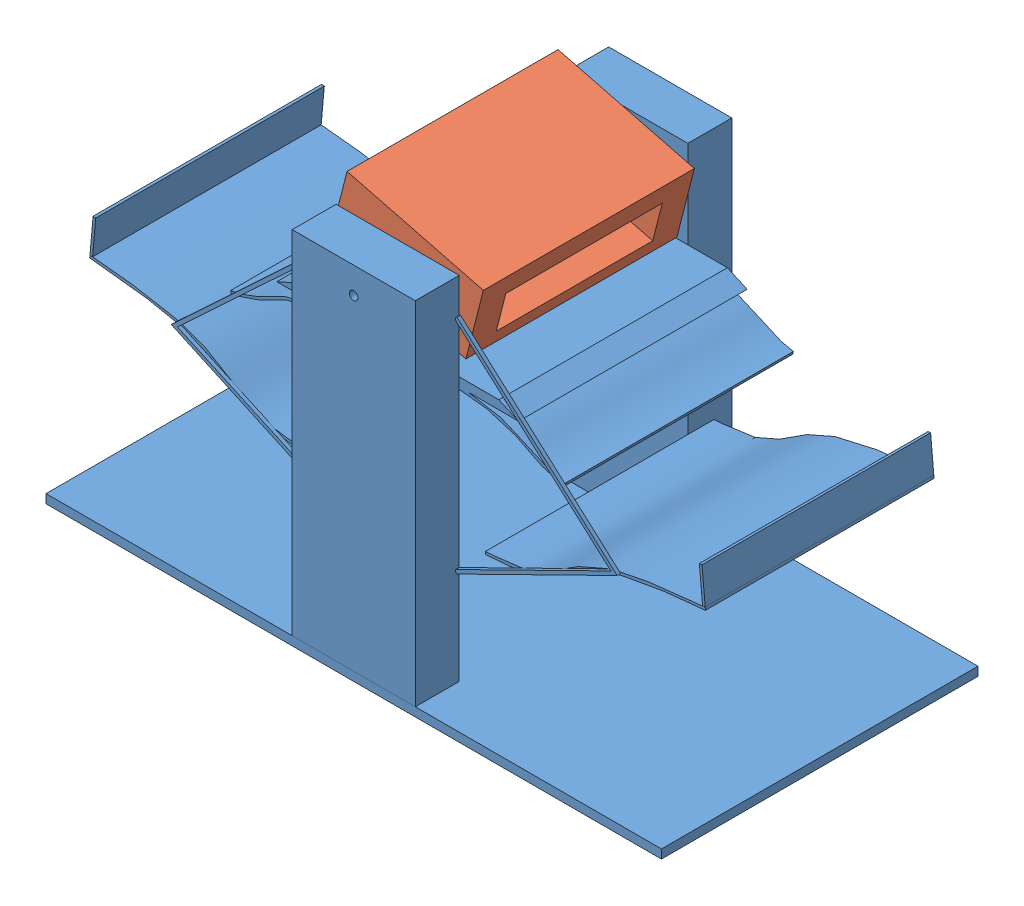
SolidWorks assembly sortiermaschine, configuration Standard. Lengths in mm.
Overall size (350.14 219.29 180).
2 component instances, 2 part files, 2 mates.
Components (placement in the parent):
- drehteildings1halterung-2: drehteildings1halterung [Standard] at (-22.9241 -124.1782 0) size (350.14 205 180)
- drehteildings1-1: drehteildings1 [Standard] at (-35.0188 48.2714 23.9252) x (0 0 -1) z (0.968813 -0.247791 0) size (160 40 80)
Mates (geometry in assembly coordinates):
- Abstand2: distance = 5 mm anti-aligned: plane of drehteildings1halterung-2 through (-58.3402 -65.0875 65) normal (0 0 -1); unknown of drehteildings1-1
- Deckungsgleich3: coincident anti-aligned: axis of drehteildings1halterung-2; unknown of drehteildings1-1
